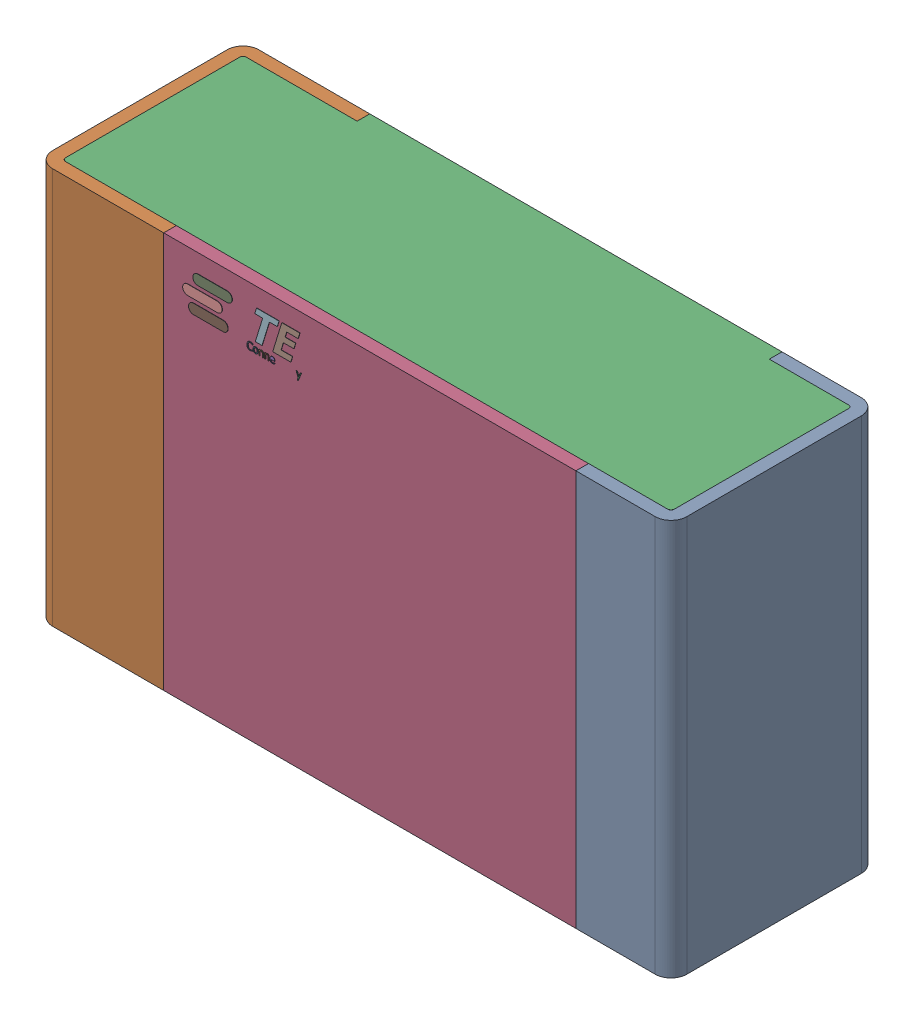
SolidWorks assembly R11.step, configuration Default. Lengths in mm.
Overall size (2 1.25 0.65).
5 component instances, 4 part files, 0 mates.
Components (placement in the parent):
- Res_TE_Connectivity_CPF0805B66R5E1_eec.step-1: Res_TE_Connectivity_CPF0805B66R5E1_eec.step [Default] at (57.277 24.511 0) size (2 1.25 0.65)
  - 1.step-1: 1.step [Default] at origin size (2 1.25 0.65)
  - 2.step-1: 2.step [Default] at origin size (1.92 1.25 0.61)
  - 3.step-1: 3.step [Default] at origin size (1.3 1.25 0.04)
  - TE connectivity Logo 1 (2).step-1: TE connectivity Logo 1 (2).step [Default] at (5.4285 0.313 0.551) x (-1 0 0) z (0 0 1) size (0.37 0.13 0.11)
